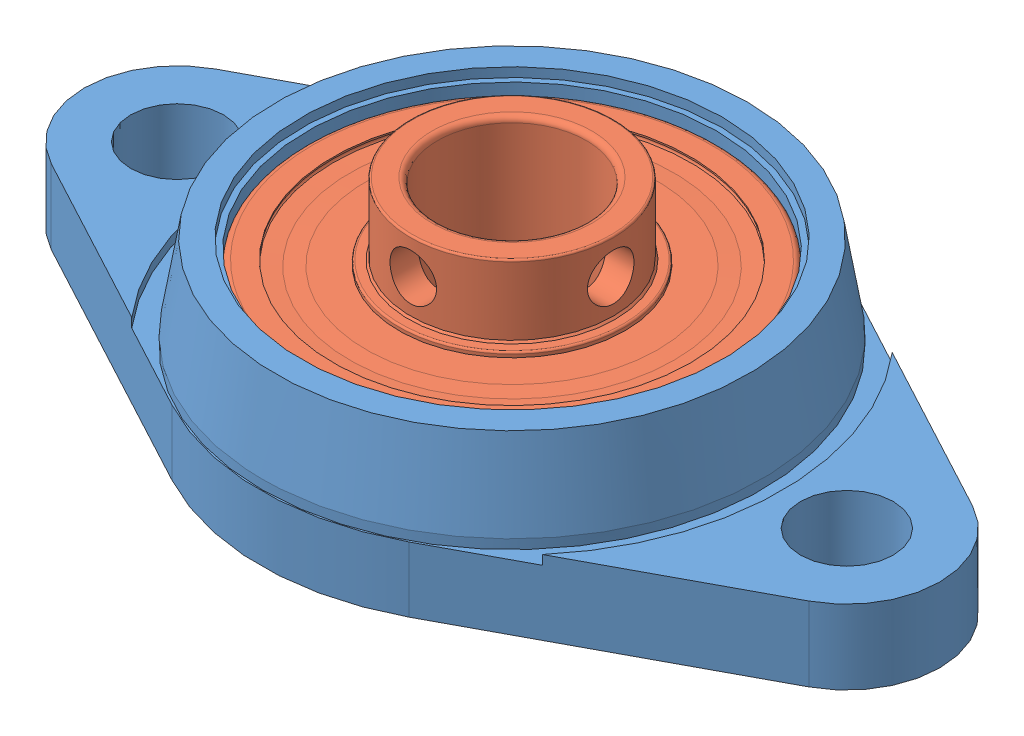
SolidWorks assembly Vòng bi KFL08, configuration Varsayılan. Lengths in mm.
Overall size (46 11.35 27).
2 component instances, 2 part files, 0 mates.
Components (placement in the parent):
- FLANGE^Vòng bi KFL08-1: FLANGE^Vòng bi KFL08 [Default] at origin size (46 8.5 27) (virtual)
- BEARING^Vòng bi KFL08-1: BEARING^Vòng bi KFL08 [Default] at (0 4 0) x (1 0 0) z (0 -1 0) size (22 22 10.85) (virtual)
